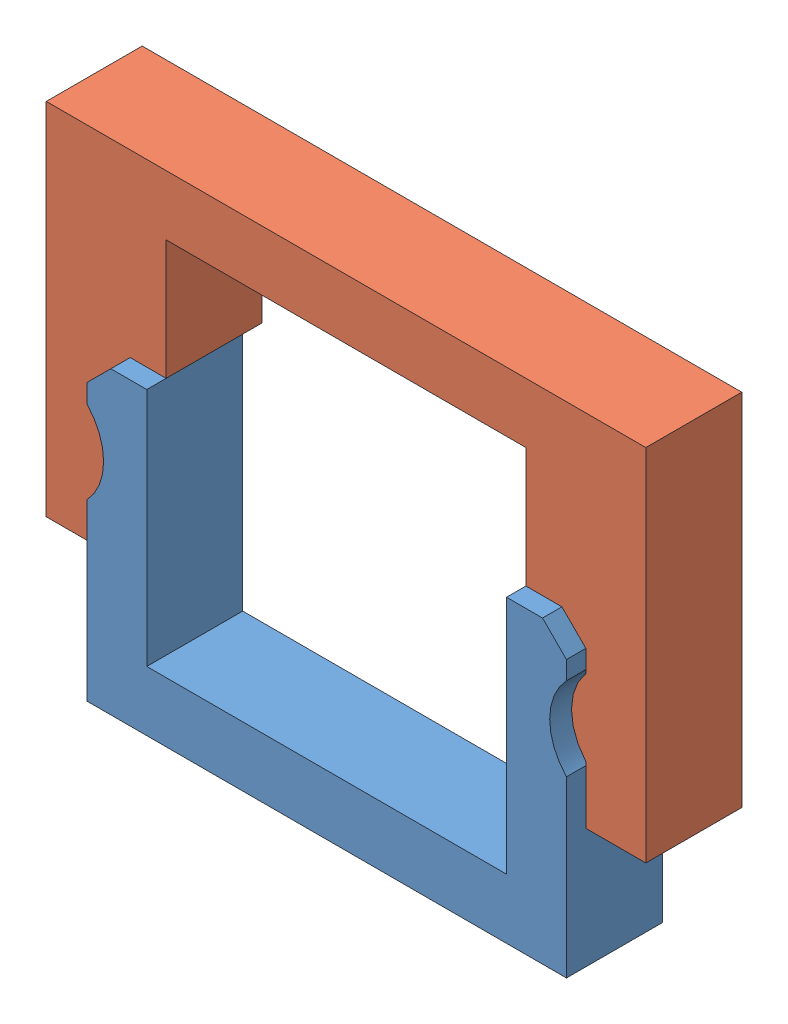
SolidWorks assembly Assem1, configuration Default. Lengths in mm.
Overall size (63.5 50.8 12.21).
2 component instances, 2 part files, 2 mates.
Components (placement in the parent):
- RepClip bottom v2.0-1: RepClip bottom v2.0 [Default] at (-0.8147 1.4313 -0.5425) size (50.8 31.75 10.16)
- RepClip top v2.0-1: RepClip top v2.0 [Default] at (60.6384 3.8593 -2.5953) x (0 0 1) z (-1 0 0) size (10.16 38.1 63.5)
Mates (geometry in assembly coordinates):
- Coincident2: coincident anti-aligned: plane of RepClip bottom v2.0-1 through (13.4028 13.8067 9.6175) normal (0.707107 0.707107 0); plane of RepClip top v2.0-1 through (15.9428 11.2667 7.5647) normal (-0.707107 -0.707107 0)
- Coincident3: coincident anti-aligned: plane of RepClip bottom v2.0-1 through (15.9428 13.8067 9.6175) normal (0 1 0); plane of RepClip top v2.0-1 through (9.5928 13.8067 7.5647) normal (0 -1 0)
